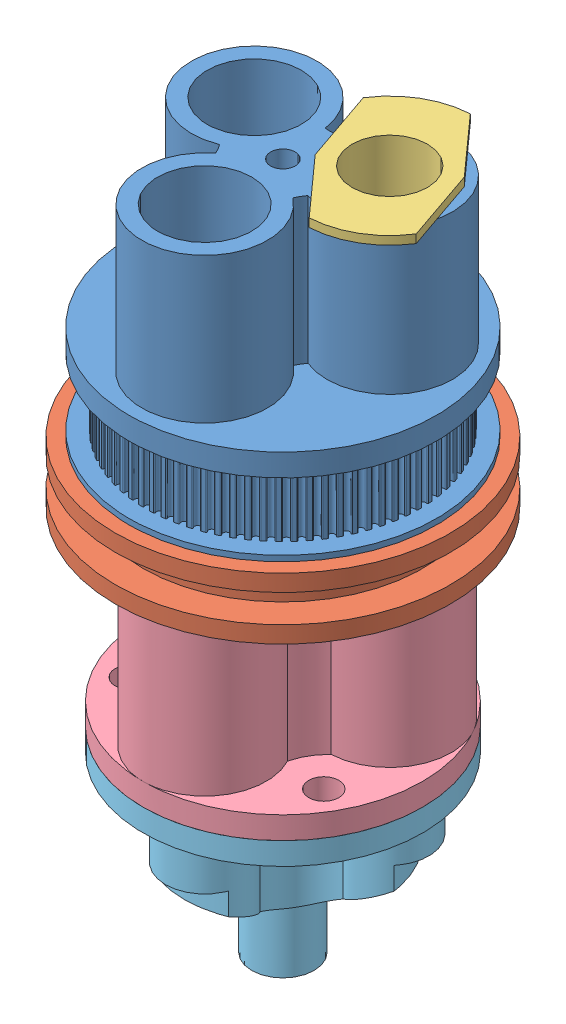
SolidWorks assembly syringe barrel assembly - one waye valve, configuration Default. Lengths in mm.
Overall size (68.3 125.51 68.3).
5 component instances, 5 part files, 10 mates.
Components (placement in the parent):
- barrel mid 1-1: barrel mid 1 [Default] at origin size (55 48.5 55)
- aluminium ring-1: aluminium ring [Default] at (0 -5.5 0) size (60 11 60)
- syringe 10 ml part1-1: syringe 10 ml part1 [Default] at (12.1244 5.5 -7) x (0 -1 0) z (-0.862176 0 0.506608) size (86.5 30.6 19.5)
- barrel bottom 1 - one way valve-1: barrel bottom 1 - one way valve [Default] at (0 -45 0) size (55 39.4 55)
- mixing chamber 2 - one way valve-2: mixing chamber 2 - one way valve [Default] at (0 -80 0) x (0.866025 0 -0.5) z (0 1 0) size (50 50 36.01)
Mates (geometry in assembly coordinates):
- Coincident1: coincident: plane of barrel mid 1-1 through (0 0 0) normal (0 -1 0); plane of aluminium ring-1 through (-30 0 0) normal (0 1 0)
- Concentric1: concentric: cylinder of barrel mid 1-1 through (0 -5.5 0) axis (0 1 0) radius 22.5; cylinder of aluminium ring-1 through (0 -11.001 0) axis (0 1 0) radius 22.8
- Concentric5: concentric: cylinder of barrel mid 1-1 through (12.1244 43 -7) axis (0 -1 0) radius 8.425; cylinder of syringe 10 ml part1-1 through (12.1244 55.6174 -7) axis (0 1 0) radius 8.25
- Coincident9: coincident: plane of barrel mid 1-1 through (0 43 0) normal (0 1 0); plane of syringe 10 ml part1-1 through (16.3039 43 0.113) normal (0 -1 0)
- Concentric7: concentric: cylinder of barrel mid 1-1 through (0 43 14) axis (0 -1 0) radius 8.425; cylinder of barrel bottom 1 - one way valve-1 through (0 -11 14) axis (0 -1 0) radius 8.425
- Concentric8: concentric: cylinder of barrel mid 1-1 through (12.1244 43 -7) axis (0 -1 0) radius 8.425; cylinder of barrel bottom 1 - one way valve-1 through (12.1244 -11 -7) axis (0 -1 0) radius 8.425
- Coincident10: coincident: plane of aluminium ring-1 through (-30 -11 0) normal (0 -1 0); plane of barrel bottom 1 - one way valve-1 through (0 -11 0) normal (0 1 0)
- Concentric9: concentric: cylinder of barrel bottom 1 - one way valve-1 through (12.1244 -11 -7) axis (0 -1 0) radius 8.425; cylinder of mixing chamber 2 - one way valve-2 through (12.1244 -44 -7) axis (0 -1 0) radius 5.35
- Concentric10: concentric: cylinder of barrel bottom 1 - one way valve-1 through (-12.1244 -11 -7) axis (0 -1 0) radius 8.425; cylinder of mixing chamber 2 - one way valve-2 through (-12.1244 -44 -7) axis (0 -1 0) radius 5.35
- Coincident11: coincident: plane of barrel bottom 1 - one way valve-1 through (0 -45 0) normal (0 -1 0); plane of mixing chamber 2 - one way valve-2 through (0 -45 0) normal (0 1 0)
